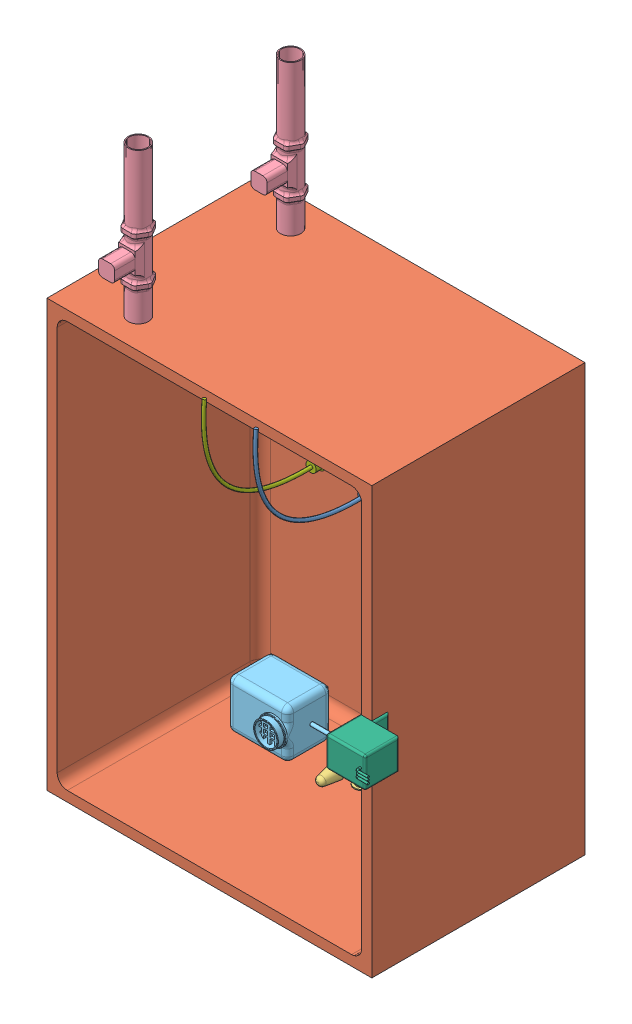
SolidWorks assembly Assem2, configuration Default. Lengths in mm.
Overall size (176.96 284 139.18).
8 component instances, 7 part files, 17 mates.
Components (placement in the parent):
- ph-1: ph [Default] at (78.5845 95.9643 61.5265) x (0 1 0) z (0 0 -1) size (58.89 12.97 101.18)
- tank-1: tank [Default] at (23.0422 17.9643 -18.4735) size (160 210 105)
- oxygen suply-1: oxygen suply [Default] at (20.6535 -72.0357 9.1331) x (0 1 0) z (0.99905 0 -0.043569) size (20.99 26.16 7.32)
- vlve controller-1: vlve controller [Default] at (-26.9578 196.9643 66.5265) x (-0.494153 0 0.869375) z (0 -1 0) size (21.75 16.84 79)
- vlve controller-2: vlve controller [Default] at (-26.9578 196.9643 -8.4735) x (-0.494153 0 0.869375) z (0 -1 0) size (21.75 16.84 79)
- food-1: food [Default] at (97.0422 15.0883 94.0265) x (0 1 0) z (1 0 0) size (24.07 25.83 42.64)
- servo-2: servo [Default] at (97.0422 15.0883 94.0265) x (0 1 0) z (1 0 0) size (15 26.78 25.32)
- temperature-1: temperature [Default] at (53.1363 95.9643 61.5265) x (0 1 0) z (0 0 -1) size (58.89 12.97 101.18)
Mates (geometry in assembly coordinates):
- Coincident1: coincident anti-aligned: plane of ph-1 through (78.5845 117.9643 56.5265) normal (0 1 0); plane of tank-1 through (98.0422 117.9643 81.5265) normal (0 -1 0)
- Distance3: distance = 20 mm aligned: plane of ph-1 through (78.5845 95.9643 61.5265) normal (0 0 1); plane of tank-1 through (23.0422 17.9643 81.5265) normal (0 0 1)
- Concentric3: concentric aligned: cylinder of tank-1 through (23.0422 -47.0357 6.5265) axis (0 -1 0) radius 2.5; cylinder of oxygen suply-1 through (23.0422 -72.0357 6.5265) axis (0 -1 0) radius 2.5
- Coincident9: coincident aligned: plane of tank-1 through (103.0422 -87.0357 81.5265) normal (0 -1 0); circle of oxygen suply-1
- Concentric4: concentric aligned: cylinder of tank-1 through (-26.9578 74.9643 66.5265) axis (0 1 0) radius 5; cylinder of vlve controller-1 through (-26.9578 117.9643 66.5265) axis (0 1 0) radius 5
- Coincident10: coincident aligned: plane of tank-1 through (98.0422 117.9643 81.5265) normal (0 -1 0); circle of vlve controller-1
- Parallel1: parallel aligned: plane of tank-1 through (-56.9578 122.9643 81.5265) normal (-1 0 0); plane of vlve controller-1 through (-30.9578 196.9643 82.1555) normal (-1 0 0)
- Concentric5: concentric aligned: cylinder of tank-1 through (-26.9578 74.9643 -8.4735) axis (0 1 0) radius 5; cylinder of vlve controller-2 through (-26.9578 117.9643 -8.4735) axis (0 1 0) radius 5
- Coincident12: coincident aligned: plane of tank-1 through (98.0422 117.9643 81.5265) normal (0 -1 0); circle of vlve controller-2
- Parallel2: parallel aligned: plane of tank-1 through (-56.9578 122.9643 81.5265) normal (-1 0 0); plane of vlve controller-2 through (-30.9578 196.9643 7.1555) normal (-1 0 0)
- Coincident17: coincident anti-aligned: plane of tank-1 through (23.0422 17.9643 81.5265) normal (0 0 1); plane of servo-2 through (127.0422 22.5883 81.5265) normal (0 0 -1)
- Coincident18: coincident anti-aligned: plane of tank-1 through (98.0422 117.9643 81.5265) normal (-1 0 0); plane of servo-2 through (98.0422 15.0883 94.0265) normal (1 0 0)
- Concentric6: concentric aligned: cylinder of food-1 through (82.0422 15.1181 90.0904) axis (1 0 0) radius 0.9044; cylinder of servo-2 through (82.0422 15.1181 90.0904) axis (1 0 0) radius 0.9044
- Coincident19: coincident aligned: circle of food-1; plane of servo-2 through (94.6801 -40.8452 70.8771) normal (-1 0 0)
- Parallel3: parallel aligned: plane of tank-1 through (23.0422 17.9643 81.5265) normal (0 0 1); plane of food-1 through (79.0422 6.0814 102.0053) normal (0 0 1)
- Coincident21: coincident: plane of tank-1 through (98.0422 117.9643 81.5265) normal (0 -1 0); plane of temperature-1 through (53.1363 117.9643 56.5265) normal (0 1 0)
- Coincident24: coincident aligned: plane of ph-1 through (78.5845 95.9643 61.5265) normal (0 0 1); plane of temperature-1 through (53.1363 95.9643 61.5265) normal (0 0 1)
